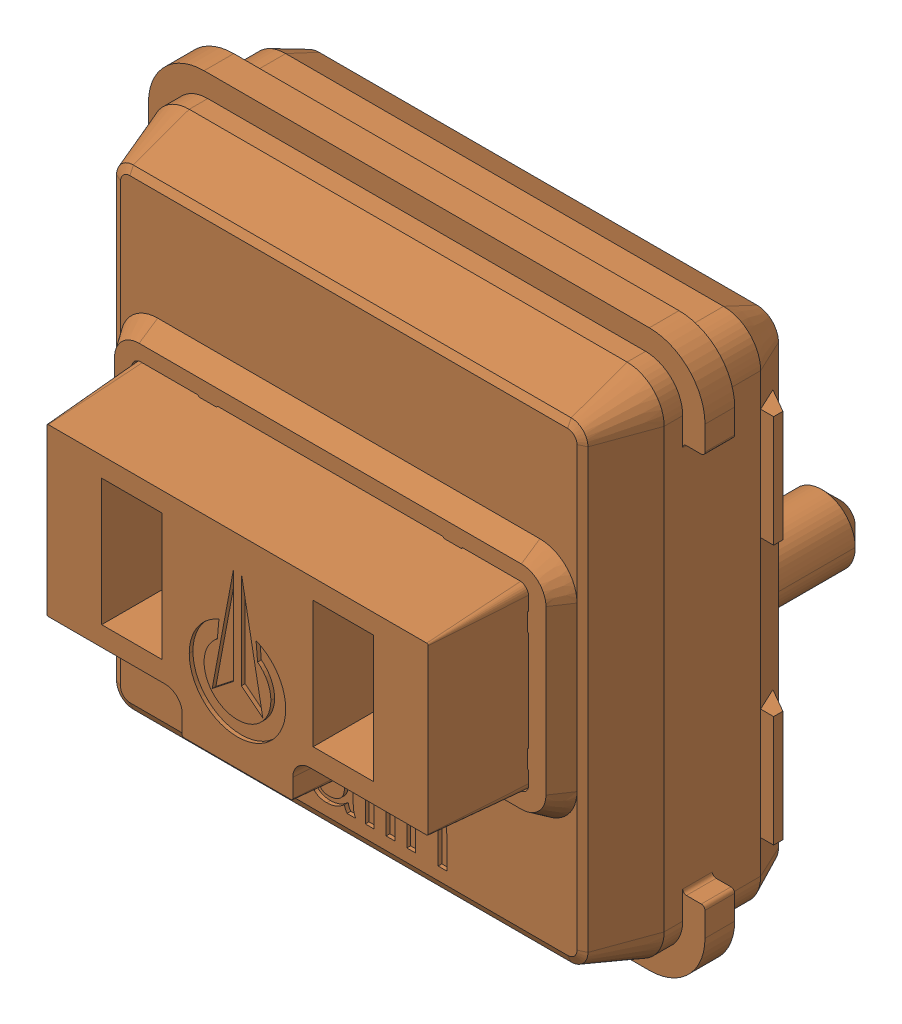
SolidWorks assembly SW2_1.step, configuration Default. Lengths in mm.
Overall size (15 15 11.1).
2 component instances, 2 part files, 0 mates.
Components (placement in the parent):
- WS2812-2020_1.step-11: WS2812-2020_1.step [Default] at (517.4468 231.0345 0.3) x (1 0 0) z (0 -1 0) size (2.2 0.86 2)
- Kailh LP Choc Burnt Orange_1.step-11: Kailh LP Choc Burnt Orange_1.step [Default] at (517.3402 226.3933 2.7) x (0 -1 0) z (-1 0 0) size (15 11.1 15)
